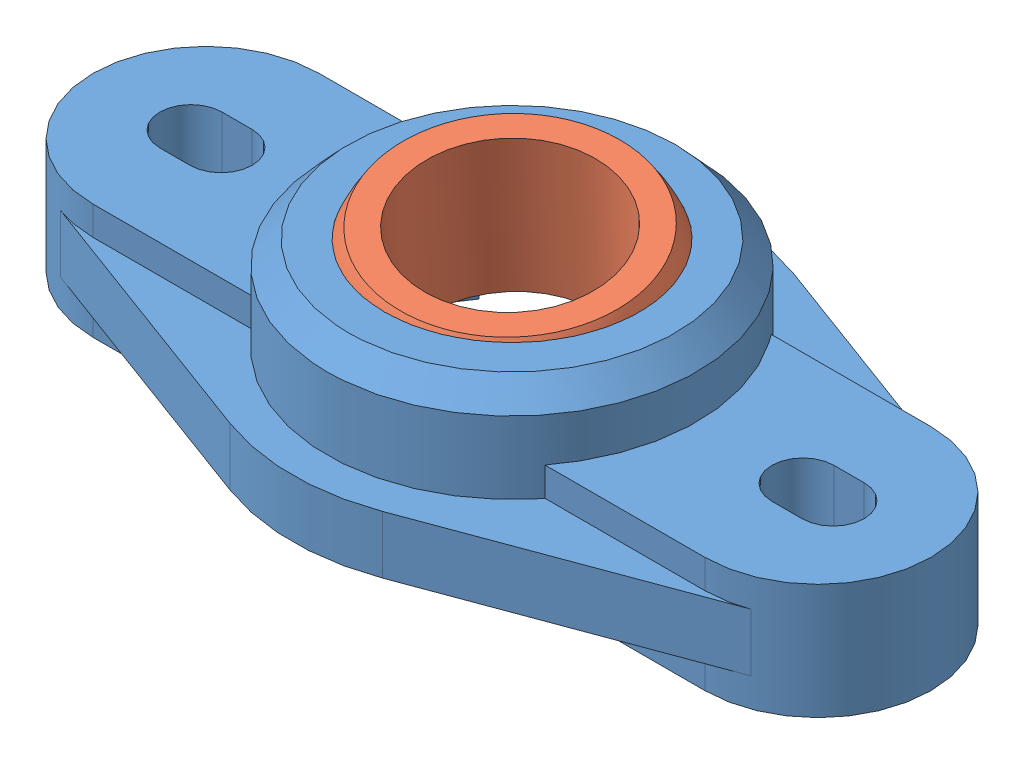
SolidWorks assembly igubal Spherical Flange, configuration Default. Lengths in mm.
Overall size (72.61 19.35 38).
2 component instances, 2 part files, 1 mates.
Components (placement in the parent):
- igubal Spherical Flange_Bearing-1: igubal Spherical Flange_Bearing [Default] at (31.8431 39.3288 52.255) size (72.61 15.75 38)
- igubal Spherical Flange_Ball-1: igubal Spherical Flange_Ball [Default] at (31.8431 45.3296 52.255) x (0.355897 0.067105 -0.932113) z (0.073493 0.99232 0.099501) size (24 24 12.7)
Mates (geometry in assembly coordinates):
- Concentric1: concentric: sphere of igubal Spherical Flange_Bearing-1; sphere of igubal Spherical Flange_Ball-1
